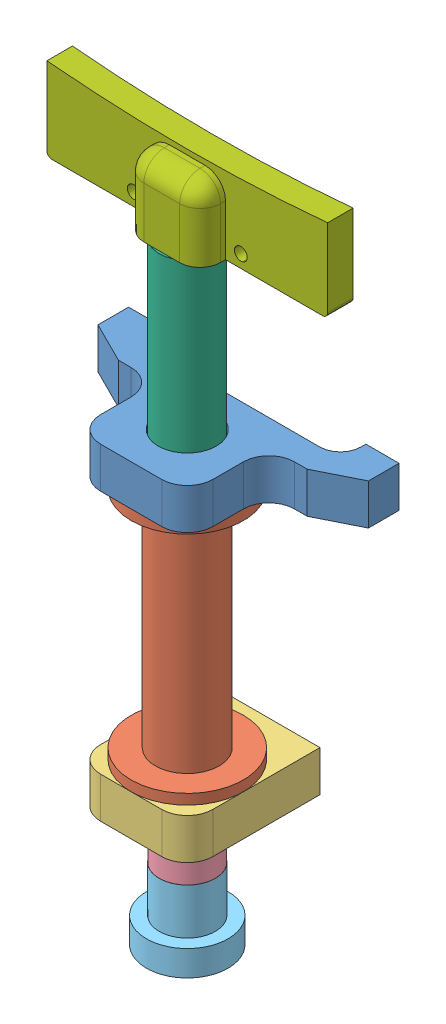
SolidWorks assembly straight kicker assembly, configuration Default. Lengths in mm.
Overall size (55 136.26 26.88).
7 component instances, 7 part files, 13 mates.
Components (placement in the parent):
- 1 straight front support-1: 1 straight front support [Default] at (-3.3783 -5.3013 -10.3333) size (53 8 26)
- 1 straight shell-1: 1 straight shell [Default] at (-3.3783 -29.3013 4.6667) x (0 -1 0) z (-0.083192 0 0.996533) size (52 22 22)
- 1 straight rear support-1: 1 straight rear support [Default] at (7.6217 -61.3013 -6.3333) x (0 1 0) z (0 0 1) size (8 22 26)
- 1 straight plunger-1: 1 straight plunger [Default] at (-3.3783 -43.2539 4.6667) x (0 1 0) z (0 0 1) size (55 11 11)
- 1 straight plunger rear-1: 1 straight plunger rear [Default] at (-3.3783 -76.9039 4.6667) x (0 1 0) z (0 0 1) size (14 16 16)
- 1 straight kicker middle-1: 1 straight kicker middle [Default] at (-3.3783 9.2461 4.6667) x (0 -1 0) z (0.924225 0 -0.381849) size (71 10.98 10.98)
- 1 straight kicker front-1: 1 straight kicker front [Default] at (-3.3783 35.2461 -0.3333) x (-1 0 0) z (0 0 1) size (55 16.26 10)
Mates (geometry in assembly coordinates):
- Concentric1: concentric anti-aligned: circle of 1 straight front support-1; circle of 1 straight shell-1
- Coincident2: coincident anti-aligned: plane of 1 straight front support-1 through (-3.3783 -5.3013 -10.3333) normal (0 -1 0); plane of 1 straight shell-1 through (-3.3783 -5.3013 4.6667) normal (0 1 0)
- Concentric2: concentric anti-aligned: circle of 1 straight shell-1; circle of 1 straight rear support-1
- Coincident4: coincident anti-aligned: plane of 1 straight shell-1 through (-3.3783 -53.3013 4.6667) normal (0 -1 0); plane of 1 straight rear support-1 through (7.6217 -53.3013 -6.3333) normal (0 1 0)
- Coincident5: coincident aligned: plane of 1 straight front support-1 through (-29.8783 2.6987 -10.3333) normal (0 0 -1); plane of 1 straight rear support-1 through (7.6217 -61.3013 -10.3333) normal (0 0 -1)
- Concentric3: concentric aligned: cylinder of 1 straight plunger-1 through (-3.3783 -70.7539 4.6667) axis (0 1 0) radius 2.4585; cylinder of 1 straight plunger rear-1 through (-3.3783 -84.7539 4.6667) axis (0 1 0) radius 3.1
- Coincident6: coincident anti-aligned: plane of 1 straight plunger-1 through (-8.8783 -70.7539 4.6667) normal (0 -1 0); plane of 1 straight plunger rear-1 through (-6.4783 -70.7539 4.6667) normal (0 1 0)
- Concentric4: concentric aligned: circle of 1 straight plunger-1; circle of 1 straight kicker middle-1
- Coincident7: coincident anti-aligned: plane of 1 straight plunger-1 through (-7.3783 -25.7539 4.6667) normal (0 1 0); plane of 1 straight kicker middle-1 through (-5.4738 -25.7539 -0.4053) normal (0 -1 0)
- Concentric5: concentric anti-aligned: circle of 1 straight kicker middle-1; circle of 1 straight kicker front-1
- Coincident8: coincident anti-aligned: circle of 1 straight kicker middle-1; plane of 1 straight kicker front-1 through (24.1217 35.2461 4.6667) normal (0 -1 0)
- Concentric6: concentric anti-aligned: cylinder of 1 straight shell-1 through (-3.3783 -5.3013 4.6667) axis (0 -1 0) radius 5.7; cylinder of 1 straight plunger-1 through (-3.3783 -70.7539 4.6667) axis (0 1 0) radius 5.5
- Parallel1: parallel aligned: plane of 1 straight front support-1 through (-29.8783 2.6987 -10.3333) normal (0 0 -1); plane of 1 straight kicker front-1 through (-3.3783 350.2461 -0.3333) normal (0 0 -1)
